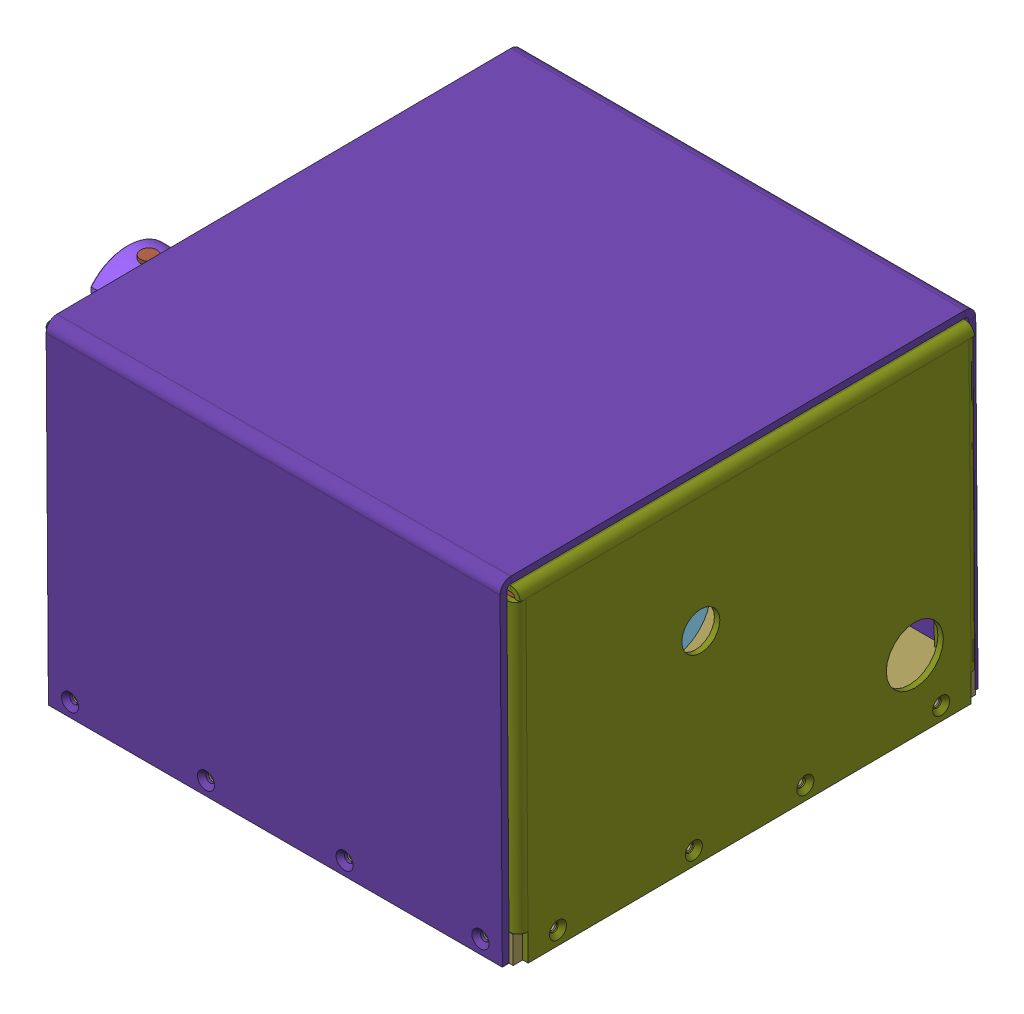
SolidWorks assembly Interferometer assembly, configuration Default. Lengths in mm.
Overall size (211 124.23 175.86).
21 component instances, 17 part files, 36 mates.
Components (placement in the parent):
- step_68636.step-1: step_68636.step [Default] at (40.039 -44.6671 -9.5355) x (0.999987 -0.000036 0.005042) z (-0.005042 -0.007058 0.999962) size (68.43 21 147.5)
- iges_68454.igs-1: iges_68454.igs [Default] at (85.7356 92.6203 -24.8825) x (0 0 1) z (-1 0 0) size (35.62 33.53 128.33)
- U200-A3K-1: U200-A3K [U200-A] at (22.4859 47.0596 -56.1191) x (0 0.007058 -0.999975) z (1 0 0) size (76.15 75.89 53.49)
- Newport-U200-A3K interface-1: Newport-U200-A3K interface [Default] at (30.4234 13.8163 -65.2897) x (0.005042 0.007058 -0.999962) z (0.999987 -0.000036 0.005042) size (45 7.6 15)
- kineflex coupler-1: kineflex coupler [Default] at (80.9067 56.435 -66.4155) x (0 -0.007058 0.999975) z (0 0.999975 0.007058) size (31.7 64 31.7)
- glass cube assembly-1: glass cube assembly [Default] at (36.5504 56.3403 -64.9895) x (0 -0.007058 0.999975) z (-1 0 0) size (50.8 52.69 35)
  - glass cube holder-1: glass cube holder [Default] at (0 0 3.7888) x (0 -1 0) z (0 0 1) size (52.69 50.8 35)
  - interferometer glass cube-1: interferometer glass cube [Default] at (-10 0 6.2888) x (1 0 0) z (0 -1 0) size (20 32.5 20)
- in coupler-1: in coupler [Default] at (-22.3065 18.0175 -57.3127) x (0 0.007058 -0.999975) z (0 0.999975 0.007058) size (35 39 36)
  - in coupler-1: in coupler [Default] at (9.3737 -6.068 38.3523) size (35 39 35)
  - in coupler insert-1: in coupler insert [Default] at (9.3737 -5.068 38.3523) x (0 0 -1) z (1 0 0) size (21 38 21)
  - 3-16in steel ball-1: 3-16in steel ball [Default] at (9.3737 24.932 46.2404) x (0.909397 -0.194542 -0.367627) z (0.362197 0.804922 0.470015) size (4.76 4.76 4.76)
  - 3-16in steel ball-2: 3-16in steel ball [Default] at (9.3737 1.932 46.237) x (-0.904215 0.348198 0.247294) z (0.351952 0.935526 -0.030362) size (4.76 4.76 4.76)
  - M6x1.0x4 set screw mock up-1: M6x1.0x4 set screw mock up [Default] at (9.3737 24.932 52.8523) x (-0.266389 0.963866 0) z (0.963866 0.266389 0) size (6 4 6)
  - M6x1.0x4 set screw mock up-2: M6x1.0x4 set screw mock up [Default] at (9.3737 1.932 52.8523) x (-0.081209 0.996697 0) z (0.996697 0.081209 0) size (6 4 6)
- new base-1: new base [Default] at (90.0973 -16.9568 -97.5406) x (1 0 0) z (0 -0.007058 0.999975) size (170 10 170)
- coupler mount 1-1: coupler mount 1 [Default] at (-11.8954 -7.1349 -72.2674) x (1 0 0) z (0 -0.007058 0.999975) size (20 83 34.7)
- coupler mount 2-1: coupler mount 2 [Default] at (76.5636 72.8536 -70.3528) x (-1 0 0) z (0 -0.007058 0.999975) size (40 80 31.7)
- box front-1: box front [Default] at (-18.7385 47.2669 -91.2872) x (0 -0.007058 0.999975) z (-1 0 0) size (170 120.5 15)
- box back-1: box back [Default] at (155.7615 68.8503 -86.0064) x (0 -0.007058 0.999975) z (-1 0 0) size (170 120 15)
- lid-1: lid [Default] at (121.528 103.1846 -46.3118) x (0 0.007058 -0.999975) z (-1 0 0) size (175 123 167)
Mates (geometry in assembly coordinates):
- Concentric4: concentric aligned: cylinder of U200-A3K-1 through (30.4234 21.4162 -65.236) axis (0 -0.999975 -0.007058) radius 2.159; cylinder of Newport-U200-A3K interface-1 through (30.4234 21.4162 -65.236) axis (0 -0.999975 -0.007058) radius 2.15
- Coincident14: coincident anti-aligned: plane of U200-A3K-1 through (38.3609 21.2145 -36.6617) normal (0 -0.999975 -0.007058); plane of Newport-U200-A3K interface-1 through (30.4234 21.4162 -65.236) normal (0 0.999975 0.007058)
- Coincident15: coincident anti-aligned: plane of step_68636.step-1 through (50.1102 14.0775 -102.2899) normal (0 0.999975 0.007058); plane of Newport-U200-A3K interface-1 through (30.4234 13.8163 -65.2897) normal (0 -0.999975 -0.007058)
- Coincident41: coincident: line of kineflex coupler-1 through (156.2569 56.435 -66.4155) axis (-1 0 0)
- Distance4: distance = 12 mm aligned: plane of Newport-U200-A3K interface-1 through (37.8099 21.2571 -42.6991) normal (0.999987 -0.000036 0.005042); plane of step_68636.step-1 through (50.1102 14.0775 -102.2899) normal (0.999987 -0.000036 0.005042)
- Distance5: distance = 11.3 mm aligned: plane of step_68636.step-1 through (49.8667 10.0367 -54.0179) normal (-0.005042 -0.007058 0.999962); plane of Newport-U200-A3K interface-1 through (37.8099 21.2571 -42.6991) normal (-0.005042 -0.007058 0.999962)
- Coincident45: coincident anti-aligned: plane of step_68636.step-1 through (27.7334 -7.4491 -27.7519) normal (0 -0.999975 -0.007058); plane of new base-1 through (90.0973 -6.957 -97.47) normal (0 0.999975 0.007058)
- Coincident48: coincident anti-aligned: plane of new base-1 through (90.0973 -6.957 -97.47) normal (0 0.999975 0.007058); plane of coupler mount 1-1 through (-11.8954 -7.1349 -72.2674) normal (0 -0.999975 -0.007058)
- Coincident52: coincident anti-aligned: plane of new base-1 through (90.0973 -6.957 -97.47) normal (0 0.999975 0.007058); plane of coupler mount 2-1 through (76.5636 -7.1445 -70.9174) normal (0 -0.999975 -0.007058)
- Coincident53: coincident anti-aligned: plane of in coupler-1/in coupler-1 through (-16.2385 56.435 -66.4155) normal (1 0 0); plane of coupler mount 1-1 through (-16.2385 75.9463 -83.4782) normal (-1 0 0)
- Parallel9: parallel aligned: plane of in coupler-1/in coupler-1 through (-19.2385 73.811 -48.7924) normal (0 0.999975 0.007058); plane of coupler mount 1-1 through (-11.8954 75.863 -71.6816) normal (0 0.999975 0.007058)
- Coincident56: coincident anti-aligned: plane of kineflex coupler-1 through (80.9067 56.435 -66.4155) normal (-1 0 0); plane of coupler mount 2-1 through (80.9067 -7.0612 -82.714) normal (1 0 0)
- Parallel10: parallel aligned: plane of kineflex coupler-1 through (83.9067 72.3965 -82.1532) normal (0 0.999975 0.007058); plane of coupler mount 2-1 through (76.5636 72.8536 -70.3528) normal (0 0.999975 0.007058)
- Parallel11: parallel aligned: plane of new base-1 through (153.7615 -6.4499 -169.3201) normal (1 0 0); plane of coupler mount 2-1 through (80.9067 -7.0612 -82.714) normal (1 0 0)
- Parallel12: parallel anti-aligned: plane of new base-1 through (-16.2385 -6.4499 -169.3201) normal (-1 0 0)
- Concentric17: concentric anti-aligned: cylinder of in coupler-1/in coupler insert-1 through (-17.2385 56.435 -66.4155) axis (-1 0 0) radius 6; cylinder of kineflex coupler-1 through (80.9067 56.435 -66.4155) axis (1 0 0) radius 3
- Coincident58: coincident aligned: plane of kineflex coupler-1 through (83.9067 72.1727 -50.454) normal (0 -0.007058 0.999975); plane of coupler mount 2-1 through (80.9067 -7.2849 -51.0148) normal (0 -0.007058 0.999975)
- Coincident61: coincident aligned: plane of new base-1 through (-16.2385 -6.4499 -169.3201) normal (-1 0 0); plane of coupler mount 1-1 through (-16.2385 75.9463 -83.4782) normal (-1 0 0)
- Coincident62: coincident aligned: plane of in coupler-1/in coupler-1 through (-19.2385 73.811 -48.7924) normal (0 -0.007058 0.999975); plane of coupler mount 1-1 through (-16.2385 75.7014 -48.779) normal (0 -0.007058 0.999975)
- Coincident63: coincident anti-aligned: plane of new base-1 through (90.0973 -6.957 -97.47) normal (0 0.999975 0.007058); plane of coupler mount 2-1 through (76.5636 -7.1445 -70.9174) normal (0 -0.999975 -0.007058)
- Coincident64: coincident anti-aligned: plane of new base-1 through (-16.2385 -6.4499 -169.3201) normal (-1 0 0); plane of box front-1 through (-16.2385 47.2669 -91.2872) normal (1 0 0)
- Coincident65: coincident aligned: plane of new base-1 through (90.0973 -16.9568 -97.5406) normal (0 -0.999975 -0.007058); plane of box front-1 through (-16.2385 -16.4497 -169.3907) normal (0 -0.999975 -0.007058)
- Coincident66: coincident aligned: plane of new base-1 through (-16.2385 -6.4499 -169.3201) normal (0 0.007058 -0.999975); plane of box front-1 through (-18.7385 47.8149 -168.9371) normal (0 0.007058 -0.999975)
- Coincident70: coincident anti-aligned: plane of new base-1 through (153.7615 -6.4499 -169.3201) normal (1 0 0); plane of box back-1 through (153.7615 68.8503 -86.0064) normal (-1 0 0)
- Coincident71: coincident aligned: plane of new base-1 through (90.0973 -16.9568 -97.5406) normal (0 -0.999975 -0.007058); plane of box back-1 through (153.7615 -16.4497 -169.3907) normal (0 -0.999975 -0.007058)
- Coincident72: coincident aligned: plane of new base-1 through (-16.2385 -6.4499 -169.3201) normal (0 0.007058 -0.999975); plane of box back-1 through (155.7615 69.4346 -168.7845) normal (0 0.007058 -0.999975)
- Coincident73: coincident anti-aligned: plane of box front-1 through (-18.7385 46.6151 1.0587) normal (0 -0.007058 0.999975); plane of lid-1 through (121.528 102.8475 1.4556) normal (0 0.007058 -0.999975)
- Coincident74: coincident anti-aligned: plane of box front-1 through (-18.7385 103.4993 -90.8903) normal (0 0.999975 0.007058); plane of lid-1 through (121.528 103.1846 -46.3118) normal (0 -0.999975 -0.007058)
- Coincident75: coincident: line of box back-1 through (152.2615 103.5372 -167.1102) axis (0 -0.007058 0.999975); plane of lid-1 through (152.2615 105.3474 1.4732) normal (1 0 0)
- Coincident76: coincident anti-aligned: plane of U200-A3K-1 through (17.7615 40.9682 -77.887) normal (-1 0 0); plane of glass cube assembly-1/glass cube holder-1 through (17.7615 56.3403 -64.9895) normal (1 0 0)
- Concentric18: concentric anti-aligned: cylinder of U200-A3K-1 through (19.2855 56.3403 -64.9895) axis (-1 0 0) radius 23.876; cylinder of glass cube assembly-1/glass cube holder-1 through (17.7615 56.3403 -64.9895) axis (1 0 0) radius 23
- Concentric19: concentric aligned: cylinder of new base-1 through (-6.2385 -17.1739 -66.785) axis (0 -0.999975 -0.007058) radius 5.5; cylinder of coupler mount 1-1 through (-6.2385 -7.1741 -66.7144) axis (0 -0.999975 -0.007058) radius 2.5
- Concentric20: concentric aligned: circle of new base-1; circle of coupler mount 2-1
- Concentric21: concentric aligned: circle of new base-1; circle of coupler mount 2-1
- Concentric23: concentric anti-aligned: circle of step_68636.step-1; circle of new base-1
- Parallel13: parallel aligned: plane of glass cube assembly-1/glass cube holder-1 through (32.7615 46.3405 -65.0601) normal (0 -0.007058 0.999975); plane of coupler mount 1-1 through (-16.2385 75.7014 -48.779) normal (0 -0.007058 0.999975)
